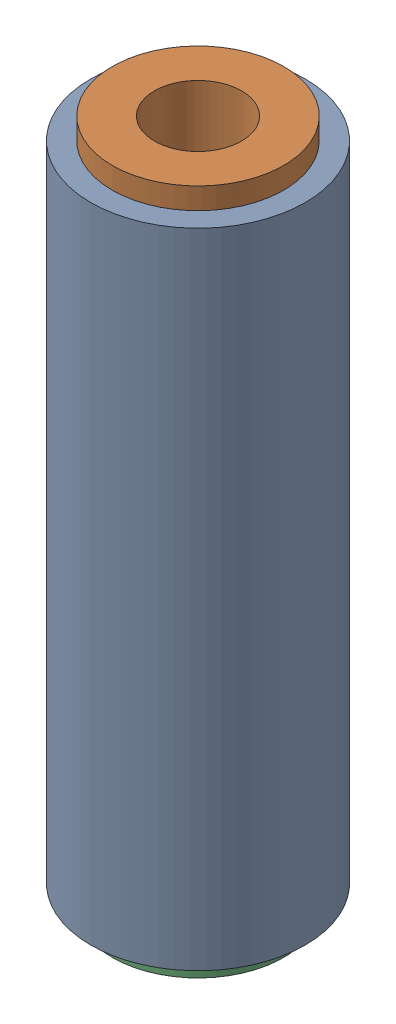
SolidWorks assembly WinchGuideRoller, configuration Default. Lengths in mm.
Overall size (18.88 50.8 18.88).
3 component instances, 2 part files, 2 mates.
Components (placement in the parent):
- StainlessRoller-1: StainlessRoller [92320A720] at (30.1625 30.1625 12.7) x (0.977234 0 0.212165) z (0 -1 0) size (15.88 15.88 47.62)
- 6362K213_WATER-RESISTANT DRY-RUNNING SLEEVE BRNG-1: 6362K213_WATER-RESISTANT DRY-RUNNING SLEEVE BRNG [6362K213] at (30.1625 57.15 12.7) x (-0.837169 0 -0.546944) z (-0.546944 0 0.837169) size (12.7 9.53 12.7)
- 6362K213_WATER-RESISTANT DRY-RUNNING SLEEVE BRNG-2: 6362K213_WATER-RESISTANT DRY-RUNNING SLEEVE BRNG [6362K213] at (30.1625 6.35 12.7) size (12.7 9.53 12.7)
Mates (geometry in assembly coordinates):
- Coincident19: coincident aligned: circle of StainlessRoller-1; circle of 6362K213_WATER-RESISTANT DRY-RUNNING SLEEVE BRNG-1
- Coincident20: coincident anti-aligned: circle of StainlessRoller-1; circle of 6362K213_WATER-RESISTANT DRY-RUNNING SLEEVE BRNG-2
